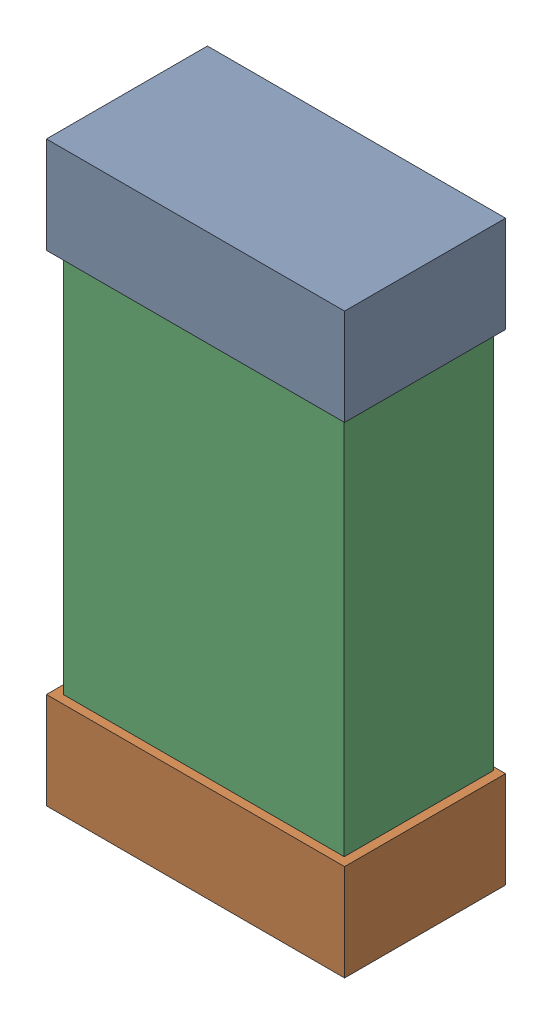
SolidWorks assembly R40, configuration Default. Lengths in mm.
Overall size (0.85 1.65 0.46).
6 component instances, 2 part files, 0 mates.
Components (placement in the parent):
- 432138512_24-1: 432138512_24 [Default] at (10.9001 62.7358 -0.8715) size (0.85 0.28 0.46)
  - Extruded-1: Extruded [Default] at origin size (0.85 0.28 0.46)
- 432138512_25-1: 432138512_25 [Default] at (10.9001 61.3643 -0.8715) size (0.85 0.28 0.46)
  - Extruded-1: Extruded [Default] at origin size (0.85 0.28 0.46)
- 432124816_12-1: 432124816_12 [Default] at (10.9001 62.0501 -0.8615) size (0.8 1.5 0.42)
  - Extruded (1)-1: Extruded (1) [Default] at origin size (0.8 1.5 0.42)
